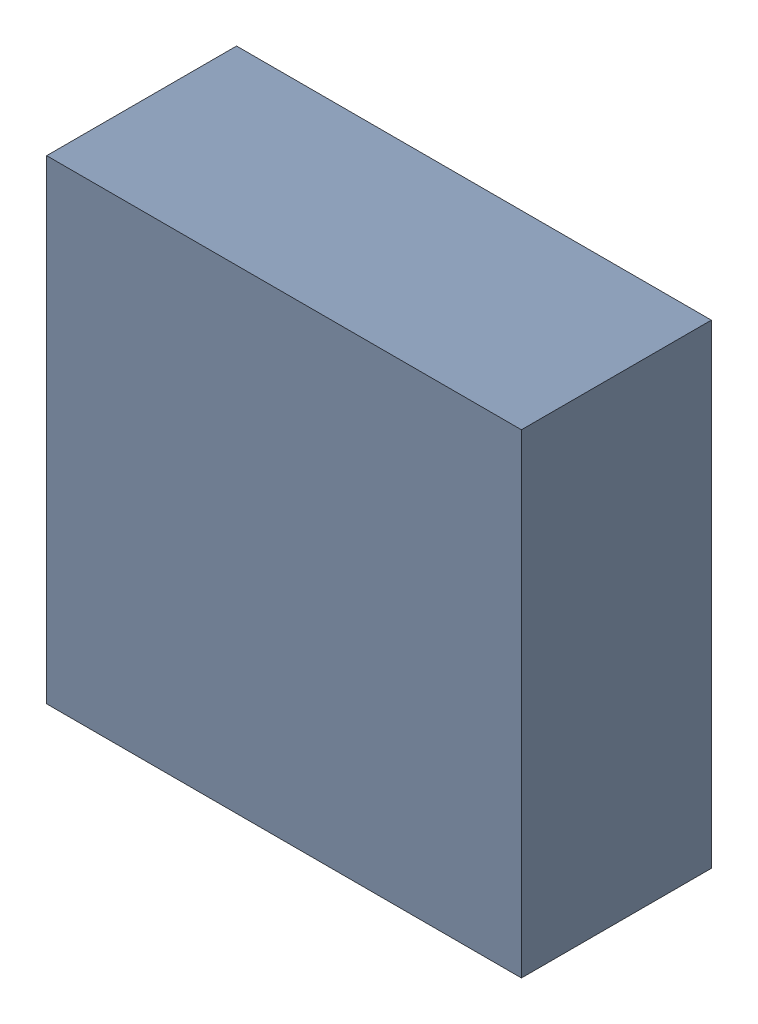
SolidWorks assembly U24, configuration ﾃﾞﾌｫﾙﾄ. Lengths in mm.
Overall size (2 2 0.8).
2 component instances, 1 part files, 0 mates.
Components (placement in the parent):
- 689262872-1: 689262872 [ﾃﾞﾌｫﾙﾄ] at (68 14 0) size (2 2 0.8)
  - Extruded_43-1: Extruded_43 [ﾃﾞﾌｫﾙﾄ] at origin size (2 2 0.8)
